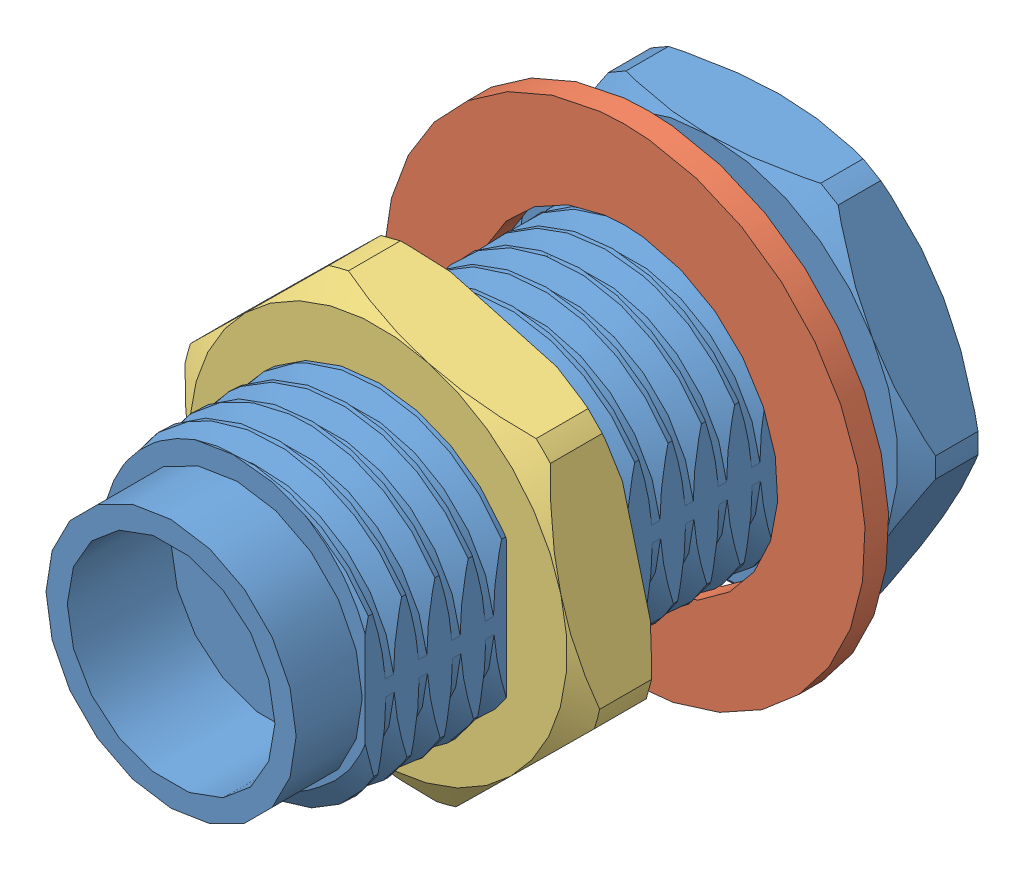
SolidWorks assembly U.FL Female Jack to SMA Female Jack Bulkhead RF Connector, configuration Default. Lengths in mm.
Overall size (10.79 10.2 14).
3 component instances, 3 part files, 2 mates.
Components (placement in the parent):
- U.FL to SMA Bulkhead-1: U.FL to SMA Bulkhead [Default] at (3.1361 7.2391 5.9943) size (9 8 14)
- U.FL to SMA Bulkhead Washer-1: U.FL to SMA Bulkhead Washer [Default] at (3.1361 7.2391 8.7872) x (-0.000136 1 0) z (0 0 1) size (10.2 10.2 0.5)
- U.FL to SMA Bulkhead Nut-1: U.FL to SMA Bulkhead Nut [Default] at (3.1361 7.2391 12.9057) x (0.964452 -0.264259 0) z (0 0 1) size (9 8 2.07)
Mates (geometry in assembly coordinates):
- Concentric1: concentric anti-aligned: cylinder of U.FL to SMA Bulkhead-1 through (3.1361 7.2391 17.4943) axis (0 0 1) radius 2.65; cylinder of U.FL to SMA Bulkhead Washer-1 through (3.1361 7.2391 9.2872) axis (0 0 -1) radius 3.25
- Concentric2: concentric aligned: cylinder of U.FL to SMA Bulkhead-1 through (3.1361 7.2391 18.8943) axis (0 0 -1) radius 2.2; cylinder of U.FL to SMA Bulkhead Nut-1 through (3.1361 7.2391 14.5057) axis (0 0 -1) radius 3.05
